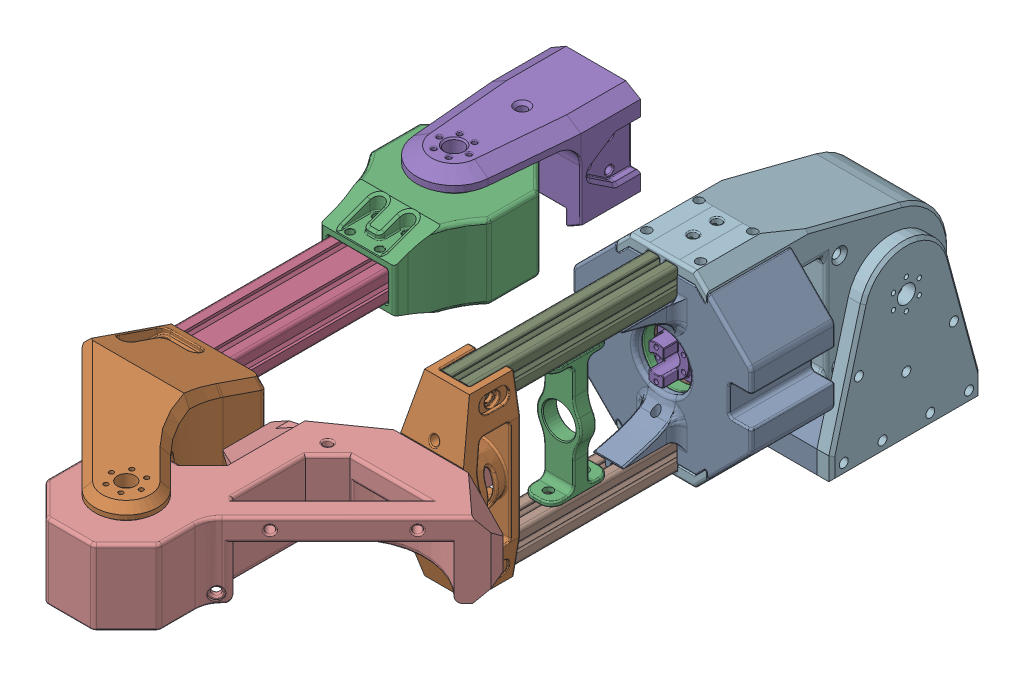
SolidWorks assembly ShinTheseusofc, configuration Valor predeterminado. Lengths in mm.
Overall size (259.74 148 493.1).
17 component instances, 17 part files, 0 mates.
Components (placement in the parent):
- cyc11a-1: cyc11a [Valor predeterminado] at origin size (48.4 48.78 4)
- cyc11a (1)-1: cyc11a (1) [Valor predeterminado] at (0.1298 0 4) x (-1 0 0) z (0 0 1) size (48.4 48.78 4)
- Facecap-1: Facecap [Valor predeterminado] at (0 0 38) size (70 70 16.04)
- Backcap-1: Backcap [Valor predeterminado] at (0 0 -1) size (70 70 16)
- Carrier121-1: Carrier121 [Valor predeterminado] at origin size (40 40 27.81)
- subcarrierA-1: subcarrierA [Valor predeterminado] at origin size (40 40 10)
- subcarrierB-1: subcarrierB [Valor predeterminado] at origin size (13.66 12 16)
- axle121-1: axle121 [Valor predeterminado] at origin size (15.32 12.03 40)
- cyc11a (2)-1: cyc11a (2) [Valor predeterminado] at origin size (48.4 48.78 4)
- cyc11a (1) (1)-1: cyc11a (1) (1) [Valor predeterminado] at origin size (48.4 48.78 4)
- shell121-1: shell121 [Valor predeterminado] at origin size (70 70 33)
- XouderJoint-1: XouderJoint [Valor predeterminado] at origin size (60.03 126.01 163)
- XouderTwist-1: XouderTwist [Valor predeterminado] at origin size (120.06 110.1 92.06)
- EubouTwist-1: EubouTwist [Valor predeterminado] at origin size (50.34 120 40.01)
- Holder-1: Holder [Valor predeterminado] at origin size (30 80 40)
- 5537T912_T-Slotted Framing-1: 5537T912_T-Slotted Framing [Valor predeterminado] at (0 -250 0) size (40 20 186.7)
- eBom-FreeParts-1: eBom-FreeParts [Valor predeterminado] at origin size (258.16 145 493.1)
